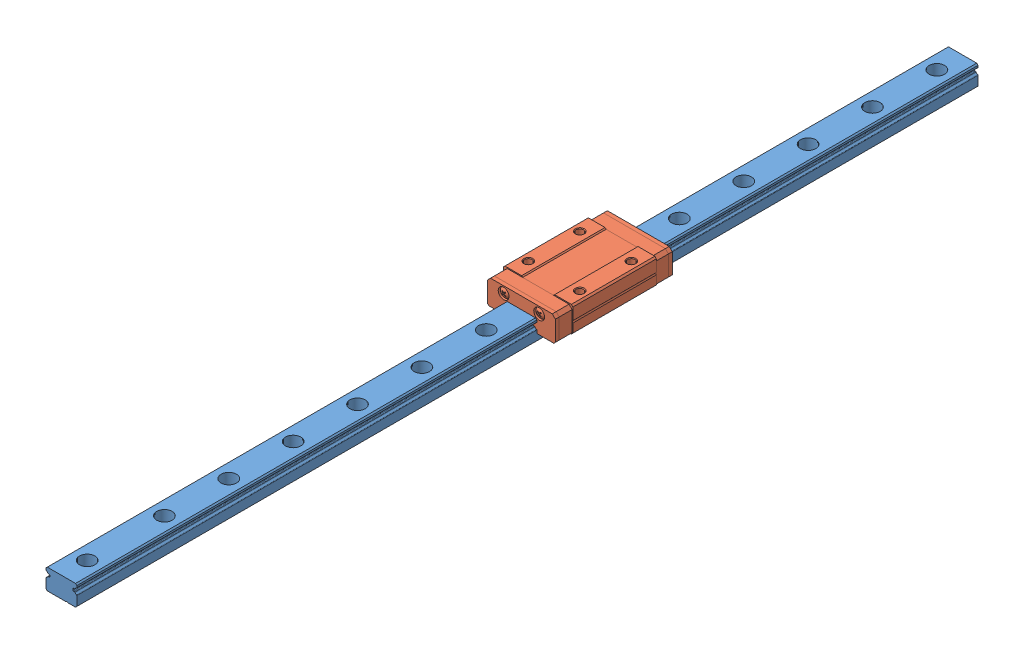
SolidWorks assembly MGN12H Assmbly, configuration Default. Lengths in mm.
Overall size (27 13.07 350).
2 component instances, 2 part files, 8 mates.
Components (placement in the parent):
- MGN12 LINEAR GUIDE RAIL, CONFIGURABLE-1: MGN12 LINEAR GUIDE RAIL, CONFIGURABLE [350 mm] at origin size (11.97 8.07 350)
- MGN12H, LINEAR GUIDE BLOCK-1: MGN12H, LINEAR GUIDE BLOCK [Default] at (0 0 -26.3412) size (27 10 47.52)
Mates (geometry in assembly coordinates):
- LimitDistance1: limit distance = 178.6412 mm aligned: plane of MGN12H, LINEAR GUIDE BLOCK-1 through (-5.75 -1.3579 -3.6412) normal (0 0 1); plane of MGN12 LINEAR GUIDE RAIL, CONFIGURABLE-1 through (-5.7336 -1.3541 175) normal (0 0 1)
- LimitDistance2: limit distance = 125.9588 mm aligned: plane of MGN12H, LINEAR GUIDE BLOCK-1 through (5.75 -1.3579 -49.0412) normal (0 0 -1); plane of MGN12 LINEAR GUIDE RAIL, CONFIGURABLE-1 through (-5.7336 -1.3541 -175) normal (0 0 -1)
- Coincident18: coincident aligned: plane of MGN12 LINEAR GUIDE RAIL, CONFIGURABLE-1 through (0 0 0) normal (0 1 0); plane of MGN12H, LINEAR GUIDE BLOCK-1 through (0 0 -26.3412) normal (0 1 0)
- Coincident19: coincident aligned: plane of MGN12 LINEAR GUIDE RAIL, CONFIGURABLE-1 through (0 0 0) normal (1 0 0)
- Coincident20: coincident aligned: plane of MGN12 LINEAR GUIDE RAIL, CONFIGURABLE-1 through (0 0 0) normal (0 1 0)
- Coincident21: coincident aligned: plane of MGN12 LINEAR GUIDE RAIL, CONFIGURABLE-1 through (0 0 0) normal (0 0 1)
- Coincident22: coincident aligned: plane of MGN12 LINEAR GUIDE RAIL, CONFIGURABLE-1 through (0 0 0) normal (0 1 0); plane of MGN12H, LINEAR GUIDE BLOCK-1 through (0 0 -26.3412) normal (0 1 0)
- Coincident23: coincident aligned: plane of MGN12 LINEAR GUIDE RAIL, CONFIGURABLE-1 through (0 0 0) normal (1 0 0); plane of MGN12H, LINEAR GUIDE BLOCK-1 through (0 0 -26.3412) normal (1 0 0)
